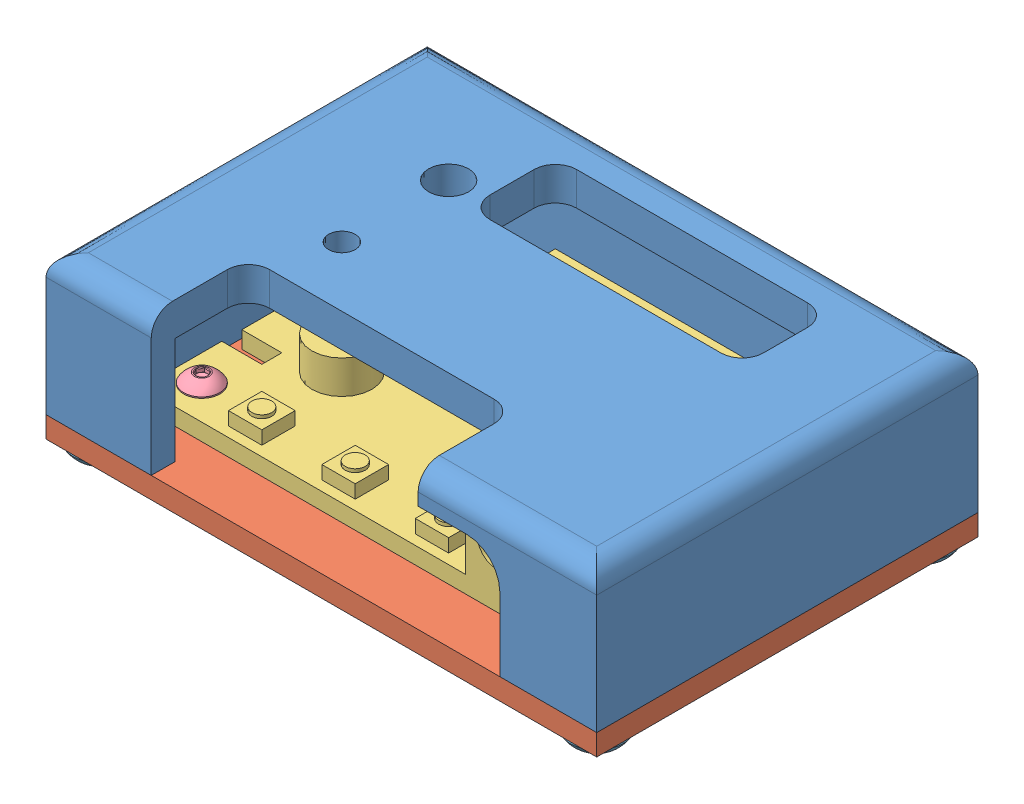
SolidWorks assembly ASY-00248, configuration Default. Lengths in mm.
Overall size (85.52 26.54 60.12).
11 component instances, 5 part files, 11 mates.
Components (placement in the parent):
- MCH-00648-1: MCH-00648 [Default] at (0 3.175 0) size (82.55 21.02 57.15)
- MCH-00647-1: MCH-00647 [Default] at origin size (82.55 3.17 57.15)
- MCH-00649-1: MCH-00649 [Default] at (0 4.7625 0) size (67 19.54 44)
- 92949A107_18-8 SS BUTTON HEAD HEX DRIVE SCREW-1: 92949A107_18-8 SS BUTTON HEAD HEX DRIVE SCREW [92949A107] at (-29.5 4.0831 17) x (-0.837169 0 -0.546944) z (0 1 0) size (5.41 5.41 9.75)
- 92949A107_18-8 SS BUTTON HEAD HEX DRIVE SCREW-2: 92949A107_18-8 SS BUTTON HEAD HEX DRIVE SCREW [92949A107] at (29.5 4.0831 17) x (-0.837169 0 -0.546944) z (0 1 0) size (5.41 5.41 9.75)
- 92949A107_18-8 SS BUTTON HEAD HEX DRIVE SCREW-3: 92949A107_18-8 SS BUTTON HEAD HEX DRIVE SCREW [92949A107] at (29.5 4.0831 -17) x (-0.837169 0 -0.546944) z (0 1 0) size (5.41 5.41 9.75)
- 92949A107_18-8 SS BUTTON HEAD HEX DRIVE SCREW-4: 92949A107_18-8 SS BUTTON HEAD HEX DRIVE SCREW [92949A107] at (-29.5 4.0831 -17) x (-0.837169 0 -0.546944) z (0 1 0) size (5.41 5.41 9.75)
- 92949A192_18-8 SS BUTTON HEAD HEX DRIVE SCREW-1: 92949A192_18-8 SS BUTTON HEAD HEX DRIVE SCREW [92949A192] at (-37.275 3.6576 24.575) x (-0.837169 0 -0.546944) z (0 -1 0) size (7.92 7.92 12.15)
- 92949A192_18-8 SS BUTTON HEAD HEX DRIVE SCREW-2: 92949A192_18-8 SS BUTTON HEAD HEX DRIVE SCREW [92949A192] at (37.275 3.6576 -24.575) x (-0.837169 0 -0.546944) z (0 -1 0) size (7.92 7.92 12.15)
- 92949A192_18-8 SS BUTTON HEAD HEX DRIVE SCREW-3: 92949A192_18-8 SS BUTTON HEAD HEX DRIVE SCREW [92949A192] at (37.275 3.6576 24.575) x (-0.837169 0 -0.546944) z (0 -1 0) size (7.92 7.92 12.15)
- 92949A192_18-8 SS BUTTON HEAD HEX DRIVE SCREW-4: 92949A192_18-8 SS BUTTON HEAD HEX DRIVE SCREW [92949A192] at (-37.275 3.6576 -24.575) x (-0.837169 0 -0.546944) z (0 -1 0) size (7.92 7.92 12.15)
Mates (geometry in assembly coordinates):
- Distance1: distance = 1.5875 mm anti-aligned: plane of MCH-00649-1 through (0 4.7625 0) normal (0 -1 0); plane of MCH-00647-1 through (0 3.175 0) normal (0 1 0)
- Width1: width aligned: plane of MCH-00647-1 through (112.7803 106.7493 72.7097) normal (1 0 0); plane of MCH-00649-1 through (30.2303 106.7493 72.7097) normal (-1 0 0); plane of MCH-00647-1 through (105.0053 110.8768 51.1347) normal (1 0 0); plane of MCH-00649-1 through (38.0053 110.8768 51.1347) normal (-1 0 0)
- Width2: width aligned: plane of MCH-00649-1 through (105.0053 110.8768 22.1347) normal (0 0 -1); plane of MCH-00647-1 through (105.0053 110.8768 66.1347) normal (0 0 1); plane of MCH-00649-1 through (112.7803 106.7493 15.5597) normal (0 0 -1); plane of MCH-00647-1 through (112.7803 106.7493 72.7097) normal (0 0 1)
- Coincident2: coincident anti-aligned: plane of MCH-00648-1 through (71.5053 106.7493 44.1347) normal (0 -1 0); plane of MCH-00647-1 through (71.5053 106.7493 44.1347) normal (0 1 0)
- Coincident3: coincident aligned: plane of MCH-00648-1 through (112.7803 127.7673 72.7097) normal (0 0 1); plane of MCH-00647-1 through (112.7803 106.7493 72.7097) normal (0 0 1)
- Coincident4: coincident aligned: plane of MCH-00648-1 through (30.2303 127.7673 72.7097) normal (-1 0 0); plane of MCH-00647-1 through (30.2303 106.7493 72.7097) normal (-1 0 0)
- Concentric1: concentric aligned: cylinder of MCH-00647-1 through (42.0053 106.7493 61.1347) axis (0 1 0) radius 1.1303; cylinder of 92949A107_18-8 SS BUTTON HEAD HEX DRIVE SCREW-1 through (42.0053 112.3754 61.1347) axis (0 1 0) radius 2.7051
- Coincident5: coincident anti-aligned: plane of MCH-00649-1 through (71.5053 110.8768 44.1347) normal (0 1 0); plane of 92949A107_18-8 SS BUTTON HEAD HEX DRIVE SCREW-1 through (40.5257 110.8768 63.3993) normal (0 -1 0)
- Concentric2: concentric: cylinder of MCH-00648-1 through (-37.275 3.175 24.575) axis (0 -1 0) radius 1.7272; cylinder of 92949A192_18-8 SS BUTTON HEAD HEX DRIVE SCREW-1 through (-21.4251 3.3122 18.7868) axis (0 -1 0) radius 3.9624
- Coincident6: coordinate: point of MCH-00647-1
- Coincident7: coincident anti-aligned: plane of MCH-00647-1 through (0 0 0) normal (0 -1 0); plane of 92949A192_18-8 SS BUTTON HEAD HEX DRIVE SCREW-1 through (-35.1078 0 21.2578) normal (0 1 0)
